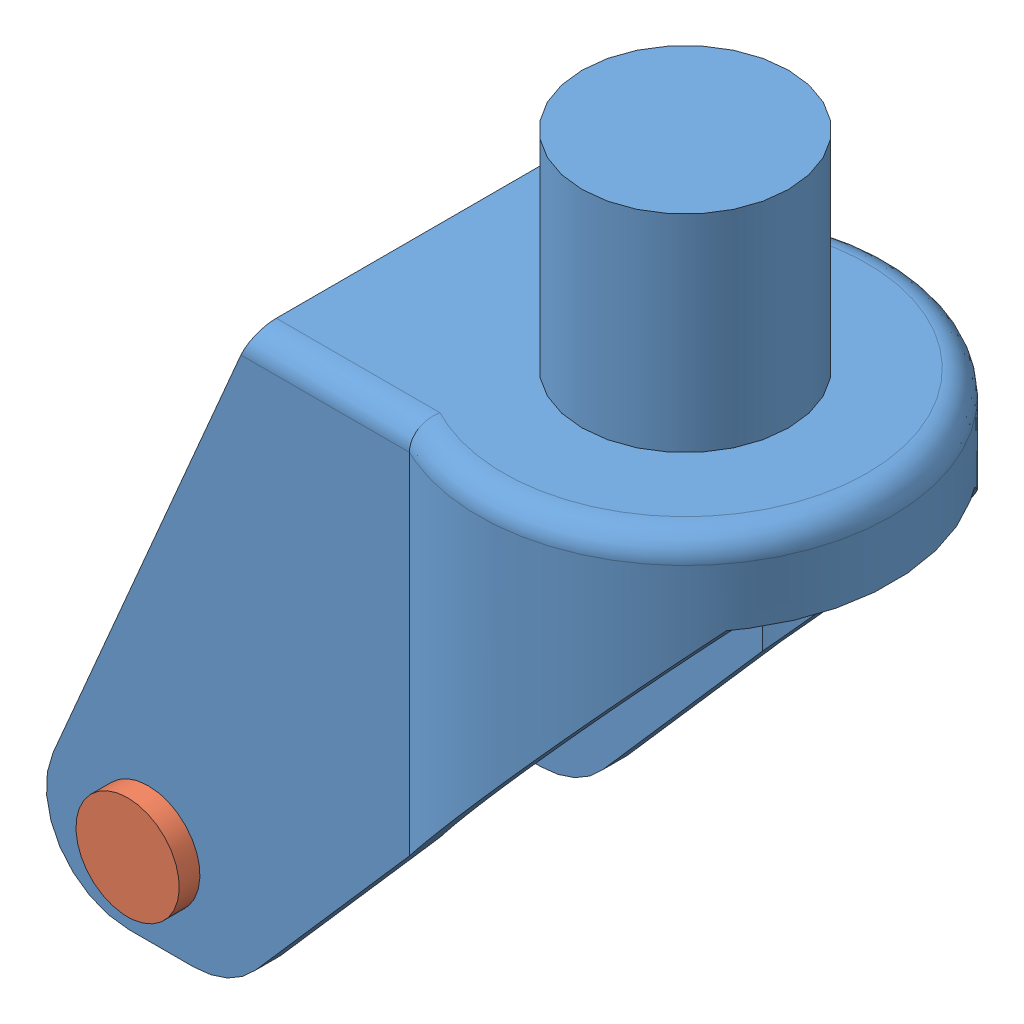
SolidWorks assembly Guide wheel, configuration Default. Lengths in mm.
Overall size (79.83 95 50).
3 component instances, 2 part files, 7 mates.
Components (placement in the parent):
- Bracket D-1: Bracket D [Default] at origin size (79.83 95 50)
- Fix wheel-1: Fix wheel [Default] at (-95.2706 -150.7189 -119.9721) (suppressed, hidden)
- Cross shaft D-1: Cross shaft D [Default] at (-42.5 -60 -25) x (1 0 0) z (0 -1 0) size (12.5 50 12.5)
Mates (geometry in assembly coordinates):
- Coincident1: coincident aligned: plane of Bracket D-1 through (0 0 0) normal (0 0 1)
- Coincident2: coincident aligned: plane of Bracket D-1 through (0 0 0) normal (0 1 0)
- Coincident3: coincident aligned: plane of Bracket D-1 through (0 0 0) normal (1 0 0)
- Width1: width: plane of Fix wheel-1/Base rim-1 through (-42.5 -60 15) normal (0 0 1); plane of Fix wheel-1/Base rim-1 through (-42.5 -60 -15) normal (0 0 -1); plane of Bracket D-1 through (-60 0 -22.5) normal (0 0 -1); plane of Bracket D-1 through (-60 0 22.5) normal (0 0 1)
- Concentric1: concentric anti-aligned: cylinder of Bracket D-1 through (-42.5 -60 -25) axis (0 0 1) radius 6.25; cylinder of Cross shaft D-1 through (-42.5 -60 25) axis (0 0 -1) radius 6.25
- Concentric2: concentric aligned: cylinder of Fix wheel-1/Base rim-1 through (-42.5 -60 15) axis (0 0 -1) radius 6.25; cylinder of Cross shaft D-1 through (-42.5 -60 25) axis (0 0 -1) radius 6.25
- Width2: width anti-aligned: plane of Cross shaft D-1 through (-42.5 -60 -25) normal (0 0 -1); plane of Cross shaft D-1 through (-42.5 -60 25) normal (0 0 1); plane of Bracket D-1 through (-60 0 22.5) normal (0 0 1); plane of Bracket D-1 through (-60 0 -22.5) normal (0 0 -1)
